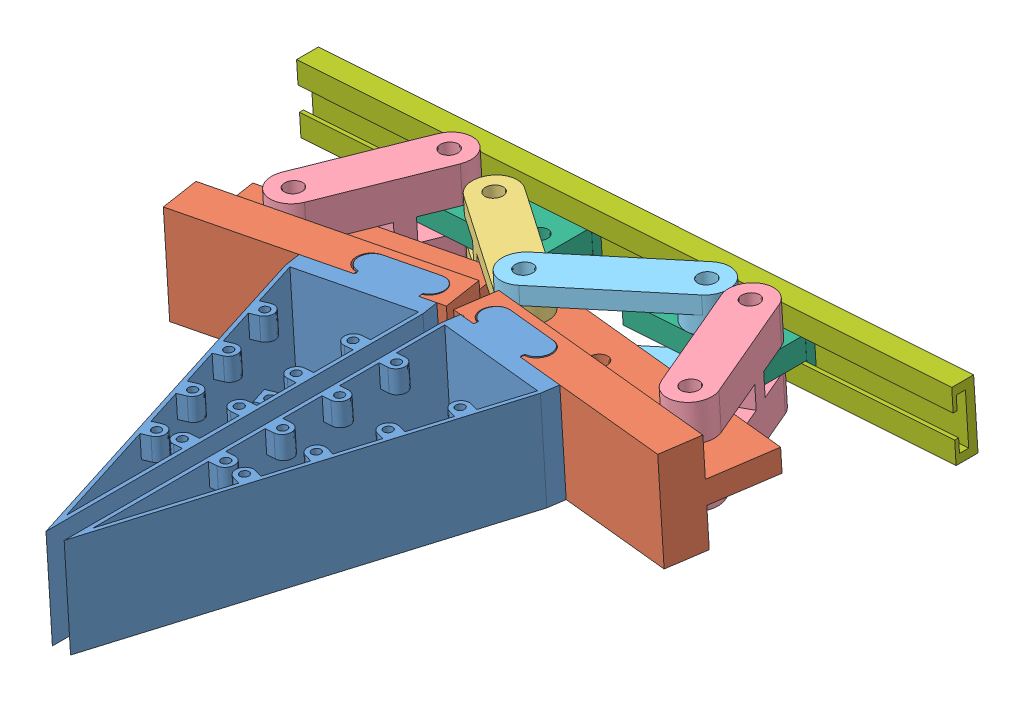
SolidWorks assembly sw-hand-closed-3, configuration Default. Lengths in mm.
Overall size (151.88 43.18 137.63).
12 component instances, 7 part files, 23 mates.
Components (placement in the parent):
- Gripper-2: Gripper [Default] at (-25.4542 1254.0052 41.8268) x (0.984986 0.06559 0.159689) z (0.066443 -0.99779 0) size (27.5 95.86 22)
- Platte-2: Platte [Default] at (-1.1431 1264.1429 -1.5058) x (0.984986 0.06559 0.159689) z (-0.159336 -0.01061 0.987167) size (67.5 22 24)
- Platte-3: Platte [Default] at (-45.8443 1266.1773 -1.5058) x (-0.984986 -0.06559 0.159689) z (0.159336 0.01061 0.987167) size (67.5 22 24)
- Gripper-3: Gripper [Default] at (-21.5332 1276.315 41.8268) x (-0.984986 -0.06559 0.159689) z (-0.066443 0.99779 0) size (27.5 95.86 22)
- Arm2-1: Arm2 [Default] at (-18.4555 1271.9599 -15.3167) x (0.814167 0.054215 0.578094) z (-0.576816 -0.03841 0.81597) size (40 13 10)
- Arm-1: Arm [Default] at (-26.8631 1254.4125 32.1886) x (-0.403942 -0.026898 0.914389) z (-0.912368 -0.060754 -0.404837) size (37 21 10)
- Arm1-1: Arm1 [Default] at (13.2423 1277.9792 45.3567) x (-0.814167 -0.054215 0.578094) z (-0.576816 -0.03841 -0.81597) size (40 8 10)
- Arm1-2: Arm1 [Default] at (-28.2662 1254.3691 -15.3167) x (-0.814167 -0.054215 0.578094) z (0.576816 0.03841 0.81597) size (40 8 10)
- Arm-2: Arm [Default] at (49.1123 1259.4716 2.086) x (0.403942 0.026898 0.914389) z (-0.912368 -0.060754 0.404837) size (37 21 10)
- Schiene-1: Schiene [Default] at (-6.7141 1263.7719 -8.9666) x (0.99779 0.066443 0) z (0 0 1) size (30 11 14.02)
- Schiene-2: Schiene [Default] at (-55.5641 1260.519 -8.9666) x (0.99779 0.066443 0) z (0 0 1) size (30 11 14.02)
- Nut-1: Nut [Default] at (51.4703 1258.1508 -3.9214) x (-0.066443 0.99779 0) z (0 0 1) size (33.29 150 5)
Mates (geometry in assembly coordinates):
- Coincident8: coincident aligned: plane of Gripper-2 through (-3.7744 1255.4488 42.1063) normal (0.066443 -0.99779 0); plane of Platte-2 through (33.7073 1257.9447 52.235) normal (0.066443 -0.99779 0)
- Coincident10: coincident anti-aligned: plane of Gripper-2 through (-16.3809 1276.6581 37.2605) normal (0.159336 0.01061 -0.987167); plane of Platte-2 through (-19.8985 1329.4827 37.2605) normal (-0.159336 -0.01061 0.987167)
- Coincident11: coincident aligned: line of Gripper-2 through (-16.3809 1276.6581 37.2605) axis (0.066443 -0.99779 0); line of Platte-2 through (-16.3809 1276.6581 37.2605) axis (0.066443 -0.99779 0)
- Coincident12: coincident anti-aligned: circle of Platte-2; circle of Platte-3
- Coincident13: coincident aligned: plane of Platte-3 through (-80.6947 1272.3754 52.235) normal (-0.066443 0.99779 0); plane of Gripper-3 through (-43.2131 1274.8713 42.1063) normal (-0.066443 0.99779 0)
- Coincident14: coincident aligned: line of Platte-3 through (-43.8881 1274.8264 39.1768) axis (0.984986 0.06559 -0.159689); line of Gripper-3 through (-43.6911 1274.8395 39.1448) axis (0.984986 0.06559 -0.159689)
- Coincident15: coincident aligned: line of Platte-3 through (-30.6065 1253.6621 37.2605) axis (-0.066443 0.99779 0); line of Gripper-3 through (-30.6065 1253.6621 37.2605) axis (-0.066443 0.99779 0)
- Coincident16: coincident aligned: circle of Platte-2; circle of Arm2-1
- Coincident17: coincident aligned: circle of Platte-3; circle of Arm-1
- Coincident18: coincident aligned: circle of Arm2-1; circle of Arm1-1
- Coincident19: coincident anti-aligned: circle of Arm2-1; circle of Arm1-2
- Coincident20: coincident anti-aligned: circle of Platte-2; circle of Arm-2
- Concentric3: concentric aligned: circle of Arm-2; circle of Schiene-1
- Concentric4: concentric aligned: cylinder of Arm1-1 through (0.2436 1277.1137 9.0226) axis (0.066443 -0.99779 0) radius 2; cylinder of Schiene-1 through (-1.075 1296.9154 9.0226) axis (0.066443 -0.99779 0) radius 2
- Concentric5: concentric anti-aligned: cylinder of Arm1-2 through (1.6256 1256.3596 9.0226) axis (-0.066443 0.99779 0) radius 2; cylinder of Schiene-1 through (-1.075 1296.9154 9.0226) axis (0.066443 -0.99779 0) radius 2
- Coincident22: coincident anti-aligned: plane of Arm-2 through (44.0353 1272.1624 -11.218) normal (0.066443 -0.99779 0); plane of Schiene-1 through (-7.0463 1268.7608 -8.9666) normal (-0.066443 0.99779 0)
- Coincident23: coincident anti-aligned: plane of Arm-1 through (-25.6502 1262.5109 32.0063) normal (-0.066443 0.99779 0); plane of Schiene-2 through (-55.5641 1260.519 -8.9666) normal (0.066443 -0.99779 0)
- Concentric8: concentric anti-aligned: cylinder of Arm-1 through (-57.199 1252.3924 9.0226) axis (-0.066443 0.99779 0) radius 2; cylinder of Schiene-2 through (-59.9029 1292.998 9.0226) axis (0.066443 -0.99779 0) radius 2
- Concentric9: concentric aligned: cylinder of Arm2-1 through (-48.3473 1269.9694 9.0226) axis (0.066443 -0.99779 0) radius 2; cylinder of Schiene-2 through (-49.925 1293.6625 9.0226) axis (0.066443 -0.99779 0) radius 2
- Coincident24: coincident anti-aligned: plane of Schiene-1 through (-14.401 1271.2777 0) normal (0 0 -1); plane of assembly through (0 0 0) normal (0 0 1)
- Coincident26: coincident aligned: line of Schiene-1 through (-14.401 1271.2777 0) axis (0.99779 0.066443 0); line of Nut-1 through (-99.3593 1265.6204 0) axis (0.99779 0.066443 0)
- Parallel2: parallel anti-aligned: plane of Gripper-2 through (-22.1494 1276.274 47.3245) normal (-0.99779 -0.066443 0); plane of Gripper-3 through (-24.838 1254.0462 47.3245) normal (0.99779 0.066443 0)
- Coincident31: coincident aligned: line of Schiene-2 through (-63.251 1268.0248 0) axis (0.99779 0.066443 0); line of Nut-1 through (-99.3593 1265.6204 0) axis (0.99779 0.066443 0)
